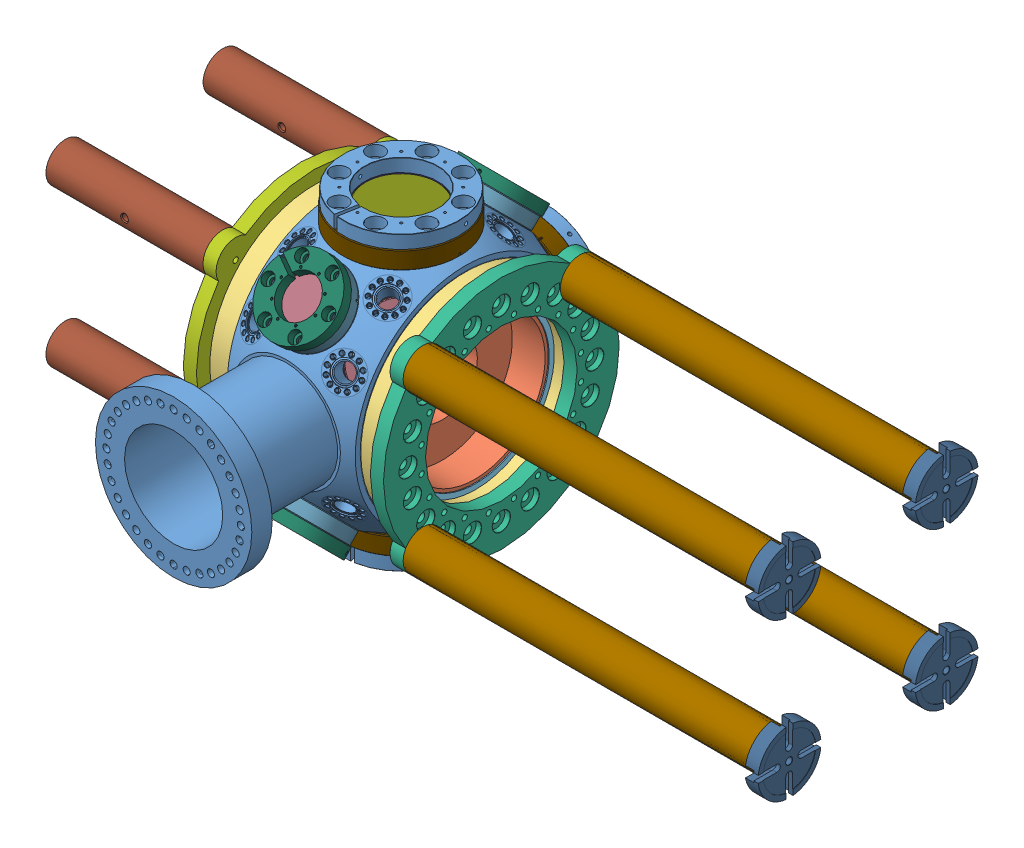
SolidWorks assembly Main Chamber Setup, configuration Default. Lengths in mm.
Overall size (770.13 358.68 400.02).
86 component instances, 19 part files, 50 mates.
Components (placement in the parent):
- Modified Kimball Chamber-1: Modified Kimball Chamber [Default] at (129.9941 206.5446 194.5806) size (246.45 225.02 343.9)
- Bucket Window-1: Bucket Window [Default] at (172.4884 96.353 297.4132) x (0 0.983185 -0.182612) z (0 0.182612 0.983185) size (236 64.03 236)
  - ISAdaptor-1: ISAdaptor [Default] at (127.1172 -28.8884 -80.9812) x (0.091876 0 -0.99577) z (-0.99577 0 -0.091876) size (142.24 51.09 142.24)
  - ISFlange-1: ISFlange [Default] at (127.1172 -30.6577 -80.9812) x (-0.182612 0 0.983185) z (-0.983185 0 -0.182612) size (202.44 22.35 202.44)
  - ISWindow-1: ISWindow [Default] at (127.1172 22.1997 -80.9812) size (68.33 6.35 68.33)
  - RecessedRing-1: RecessedRing [Default] at (127.1172 -52.3227 -80.9812) size (152.4 1 152.4)
- Bucket Window-2: Bucket Window [Default] at (87.4998 279.566 326.4313) x (0 -0.878634 -0.477495) z (0 -0.477495 0.878634) size (236 64.03 236)
  - ISAdaptor-1: ISAdaptor [Default] at (127.1172 -28.8884 -80.9812) x (0.091876 0 -0.99577) z (-0.99577 0 -0.091876) size (142.24 51.09 142.24)
  - ISFlange-1: ISFlange [Default] at (127.1172 -30.6577 -80.9812) x (-0.182612 0 0.983185) z (-0.983185 0 -0.182612) size (202.44 22.35 202.44)
  - ISWindow-1: ISWindow [Default] at (127.1172 22.1997 -80.9812) size (68.33 6.35 68.33)
  - RecessedRing-1: RecessedRing [Default] at (127.1172 -52.3227 -80.9812) size (152.4 1 152.4)
- Washer Chamber Base-1: Washer Chamber Base [Default] at (214.3221 206.5446 194.5806) x (0 -0.707107 0.707107) z (0 0.707107 0.707107) size (253.63 12.7 253.63)
- Washer Chamber Top-1: Washer Chamber Top [Default] at (45.6661 206.5446 194.5806) x (0 0.707107 0.707107) z (0 -0.707107 0.707107) size (253.63 12.7 253.63)
- Damped Post for Main Chamber Bottom-1: Damped Post for Main Chamber Bottom [Default] at (287.9394 108.1989 277.2908) x (0 0 1) z (-1 0 0) size (60.59 60.59 356.82)
  - Damped Post for Main Chamber P2_90322A235-1: Damped Post for Main Chamber P2_90322A235 [90322A235] at (-6.5102 22.1457 41.8672) size (32.66 32.53 40.54)
  - Damped Post for Main Chamber P2_90322A235-2: Damped Post for Main Chamber P2_90322A235 [90322A235] at (-6.5102 22.1457 -262.9328) x (-0.923728 -0.383049 0) z (0 0 -1) size (32.66 32.53 40.54)
  - Damped Post for Main Chamber Bottom P1-1: Damped Post for Main Chamber Bottom P1 [Default] at (-6.5102 22.1457 -281.9828) x (1 0 0) z (0 -1 0) size (38.1 342.9 38.1)
  - Damped Post for Main Chamber P3_PB2-1: Damped Post for Main Chamber P3_PB2 [Default] at (-6.5102 22.1457 -288.3328) x (1 0 0) z (0 -1 0) size (60.59 12.7 60.59)
- Damped Post for Main Chamber Bottom-2: Damped Post for Main Chamber Bottom [Default] at (287.9394 260.5989 277.2908) x (0 0 1) z (-1 0 0) size (60.59 60.59 356.82)
  - Damped Post for Main Chamber P2_90322A235-1: Damped Post for Main Chamber P2_90322A235 [90322A235] at (-6.5102 22.1457 41.8672) size (32.66 32.53 40.54)
  - Damped Post for Main Chamber P2_90322A235-2: Damped Post for Main Chamber P2_90322A235 [90322A235] at (-6.5102 22.1457 -262.9328) x (-0.923728 -0.383049 0) z (0 0 -1) size (32.66 32.53 40.54)
  - Damped Post for Main Chamber Bottom P1-1: Damped Post for Main Chamber Bottom P1 [Default] at (-6.5102 22.1457 -281.9828) x (1 0 0) z (0 -1 0) size (38.1 342.9 38.1)
  - Damped Post for Main Chamber P3_PB2-1: Damped Post for Main Chamber P3_PB2 [Default] at (-6.5102 22.1457 -288.3328) x (1 0 0) z (0 -1 0) size (60.59 12.7 60.59)
- Damped Post for Main Chamber Bottom-3: Damped Post for Main Chamber Bottom [Default] at (287.9394 108.1989 124.8908) x (0 0 1) z (-1 0 0) size (60.59 60.59 356.82)
  - Damped Post for Main Chamber P2_90322A235-1: Damped Post for Main Chamber P2_90322A235 [90322A235] at (-6.5102 22.1457 41.8672) size (32.66 32.53 40.54)
  - Damped Post for Main Chamber P2_90322A235-2: Damped Post for Main Chamber P2_90322A235 [90322A235] at (-6.5102 22.1457 -262.9328) x (-0.923728 -0.383049 0) z (0 0 -1) size (32.66 32.53 40.54)
  - Damped Post for Main Chamber Bottom P1-1: Damped Post for Main Chamber Bottom P1 [Default] at (-6.5102 22.1457 -281.9828) x (1 0 0) z (0 -1 0) size (38.1 342.9 38.1)
  - Damped Post for Main Chamber P3_PB2-1: Damped Post for Main Chamber P3_PB2 [Default] at (-6.5102 22.1457 -288.3328) x (1 0 0) z (0 -1 0) size (60.59 12.7 60.59)
- Damped Post for Main Chamber Bottom-4: Damped Post for Main Chamber Bottom [Default] at (287.9394 260.5989 124.8908) x (0 0 1) z (-1 0 0) size (60.59 60.59 356.82)
  - Damped Post for Main Chamber P2_90322A235-1: Damped Post for Main Chamber P2_90322A235 [90322A235] at (-6.5102 22.1457 41.8672) size (32.66 32.53 40.54)
  - Damped Post for Main Chamber P2_90322A235-2: Damped Post for Main Chamber P2_90322A235 [90322A235] at (-6.5102 22.1457 -262.9328) x (-0.923728 -0.383049 0) z (0 0 -1) size (32.66 32.53 40.54)
  - Damped Post for Main Chamber Bottom P1-1: Damped Post for Main Chamber Bottom P1 [Default] at (-6.5102 22.1457 -281.9828) x (1 0 0) z (0 -1 0) size (38.1 342.9 38.1)
  - Damped Post for Main Chamber P3_PB2-1: Damped Post for Main Chamber P3_PB2 [Default] at (-6.5102 22.1457 -288.3328) x (1 0 0) z (0 -1 0) size (60.59 12.7 60.59)
- Chamber Top Post_P6-5: Chamber Top Post_P6 [Default] at (-42.0322 295.4786 112.4775) x (0 1 0) z (0 0 1) size (37.74 220.47 37.75)
- Chamber Top Post_P6-6: Chamber Top Post_P6 [Default] at (-42.0322 143.0786 112.4775) x (0 1 0) z (0 0 1) size (37.74 220.47 37.75)
- Chamber Top Post_P6-7: Chamber Top Post_P6 [Default] at (-42.0322 295.4786 264.8775) x (0 1 0) z (0 0 1) size (37.74 220.47 37.75)
- Chamber Top Post_P6-8: Chamber Top Post_P6 [Default] at (-42.0322 143.0786 264.8775) x (0 1 0) z (0 0 1) size (37.74 220.47 37.75)
- 2.75 VP Assembly-1: 2.75 VP Assembly [Default] at (180.0634 70.3465 285.9142) x (0 0.707107 0.707107) z (-1 0 0) size (98.89 22.87 98.89)
  - 2.75 Window-1: 2.75 Window [Default] at (8.7044 2.1311 10.9274) size (69.34 12.71 69.34)
    - 2.75 Window P1-1: 2.75 Window P1 [Default] at (7.3044 10.0797 3.9869) size (56.02 10.92 56.02)
      - 2.75 Window P1-1-1: 2.75 Window P1-1 [Default] at (15.7152 13.9203 35.1549) size (44.88 10.92 44.88)
      - 2.75 Window P1-2-1: 2.75 Window P1-2 [Default] at (15.7152 20.9053 35.1549) x (0.940252 0 0.340481) z (0 -1 0) size (43.74 43.74 3.17)
    - 2.75 Window P2-1: 2.75 Window P2 [Default] at (23.0196 40.5099 39.1419) x (0 -1 0) z (0 0 1) size (12.71 69.34 69.34)
  - Viewport Washer 2.75-1: Viewport Washer 2.75 [Default] at (31.724 29.9411 50.0692) x (0.5 0 0.866025) z (0 -1 0) size (72.39 72.39 10.16)
- 2.75 VP Assembly-2: 2.75 VP Assembly [Default] at (127.5549 278.4333 350.2236) x (0.866025 0.353553 -0.353553) z (-0.5 0.612372 -0.612372) size (98.89 22.87 98.89)
  - 2.75 Window-1: 2.75 Window [Default] at (8.7044 2.1311 10.9274) size (69.34 12.71 69.34)
    - 2.75 Window P1-1: 2.75 Window P1 [Default] at (7.3044 10.0797 3.9869) size (56.02 10.92 56.02)
      - 2.75 Window P1-1-1: 2.75 Window P1-1 [Default] at (15.7152 13.9203 35.1549) size (44.88 10.92 44.88)
      - 2.75 Window P1-2-1: 2.75 Window P1-2 [Default] at (15.7152 20.9053 35.1549) x (0.940252 0 0.340481) z (0 -1 0) size (43.74 43.74 3.17)
    - 2.75 Window P2-1: 2.75 Window P2 [Default] at (23.0196 40.5099 39.1419) x (0 -1 0) z (0 0 1) size (12.71 69.34 69.34)
  - Viewport Washer 2.75-1: Viewport Washer 2.75 [Default] at (31.724 29.9411 50.0692) x (0.5 0 0.866025) z (0 -1 0) size (72.39 72.39 10.16)
- 2.75 VP Assembly-3: 2.75 VP Assembly [Default] at (127.5549 362.1876 122.6919) x (0.866025 -0.353553 -0.353553) z (-0.5 -0.612372 -0.612372) size (98.89 22.87 98.89)
  - 2.75 Window-1: 2.75 Window [Default] at (8.7044 2.1311 10.9274) size (69.34 12.71 69.34)
    - 2.75 Window P1-1: 2.75 Window P1 [Default] at (7.3044 10.0797 3.9869) size (56.02 10.92 56.02)
      - 2.75 Window P1-1-1: 2.75 Window P1-1 [Default] at (15.7152 13.9203 35.1549) size (44.88 10.92 44.88)
      - 2.75 Window P1-2-1: 2.75 Window P1-2 [Default] at (15.7152 20.9053 35.1549) x (0.940252 0 0.340481) z (0 -1 0) size (43.74 43.74 3.17)
    - 2.75 Window P2-1: 2.75 Window P2 [Default] at (23.0196 40.5099 39.1419) x (0 -1 0) z (0 0 1) size (12.71 69.34 69.34)
  - Viewport Washer 2.75-1: Viewport Washer 2.75 [Default] at (31.724 29.9411 50.0692) x (0.5 0 0.866025) z (0 -1 0) size (72.39 72.39 10.16)
- 2.75 VP Assembly-4: 2.75 VP Assembly [Default] at (127.5549 134.656 38.9376) x (0.866025 -0.353553 0.353553) z (-0.5 -0.612372 0.612372) size (98.89 22.87 98.89)
  - 2.75 Window-1: 2.75 Window [Default] at (8.7044 2.1311 10.9274) size (69.34 12.71 69.34)
    - 2.75 Window P1-1: 2.75 Window P1 [Default] at (7.3044 10.0797 3.9869) size (56.02 10.92 56.02)
      - 2.75 Window P1-1-1: 2.75 Window P1-1 [Default] at (15.7152 13.9203 35.1549) size (44.88 10.92 44.88)
      - 2.75 Window P1-2-1: 2.75 Window P1-2 [Default] at (15.7152 20.9053 35.1549) x (0.940252 0 0.340481) z (0 -1 0) size (43.74 43.74 3.17)
    - 2.75 Window P2-1: 2.75 Window P2 [Default] at (23.0196 40.5099 39.1419) x (0 -1 0) z (0 0 1) size (12.71 69.34 69.34)
  - Viewport Washer 2.75-1: Viewport Washer 2.75 [Default] at (31.724 29.9411 50.0692) x (0.5 0 0.866025) z (0 -1 0) size (72.39 72.39 10.16)
- 4.5 VP Assembly-1: 4.5 VP Assembly [Default] at (63.6272 104.8035 99.6116) x (0 -1 0) z (0 0 1) size (29.97 146.69 146.69)
  - Viewport 4.5_9722007-1: Viewport 4.5_9722007 [Default] at (9.7649 66.3669 94.969) size (17.27 113.54 113.54)
    - 1004602A-1: 1004602A [Default] at (1.2954 0 0) x (0 1 0) z (-1 0 0) size (73.79 73.79 15.62)
      - 1002203A-1: 1002203A [Default] at (0 0 -9.271) x (-1 0 0) z (0 0 -1) size (72.01 72.01 6.35)
      - Viewport 4.5 P1_0194302B-1: Viewport 4.5 P1_0194302B [Default] at origin size (73.79 73.79 15.49)
    - Viewport 4.5 P2_0194603B-1: Viewport 4.5 P2_0194603B [Default] at origin size (17.27 113.54 113.54)
  - Viewport Washer 4.5-1: Viewport Washer 4.5 [Default] at (27.0369 66.3669 94.969) x (0 0.382683 -0.92388) z (1 0 0) size (112.27 112.27 12.7)
- 4.5 VP Assembly-2: 4.5 VP Assembly [Default] at (16.8567 181.5727 92.8395) x (0 0 -1) z (0.92388 -0.382683 0) size (29.97 146.69 146.69)
  - Viewport 4.5_9722007-1: Viewport 4.5_9722007 [Default] at (9.7649 66.3669 94.969) size (17.27 113.54 113.54)
    - 1004602A-1: 1004602A [Default] at (1.2954 0 0) x (0 1 0) z (-1 0 0) size (73.79 73.79 15.62)
      - 1002203A-1: 1002203A [Default] at (0 0 -9.271) x (-1 0 0) z (0 0 -1) size (72.01 72.01 6.35)
      - Viewport 4.5 P1_0194302B-1: Viewport 4.5 P1_0194302B [Default] at origin size (73.79 73.79 15.49)
    - Viewport 4.5 P2_0194603B-1: Viewport 4.5 P2_0194603B [Default] at origin size (17.27 113.54 113.54)
  - Viewport Washer 4.5-1: Viewport Washer 4.5 [Default] at (27.0369 66.3669 94.969) x (0 0.382683 -0.92388) z (1 0 0) size (112.27 112.27 12.7)
- 4.5 VP Assembly-3: 4.5 VP Assembly [Default] at (196.361 308.2857 99.6116) x (0 1 0) z (0 0 1) size (29.97 146.69 146.69)
  - Viewport 4.5_9722007-1: Viewport 4.5_9722007 [Default] at (9.7649 66.3669 94.969) size (17.27 113.54 113.54)
    - 1004602A-1: 1004602A [Default] at (1.2954 0 0) x (0 1 0) z (-1 0 0) size (73.79 73.79 15.62)
      - 1002203A-1: 1002203A [Default] at (0 0 -9.271) x (-1 0 0) z (0 0 -1) size (72.01 72.01 6.35)
      - Viewport 4.5 P1_0194302B-1: Viewport 4.5 P1_0194302B [Default] at origin size (73.79 73.79 15.49)
    - Viewport 4.5 P2_0194603B-1: Viewport 4.5 P2_0194603B [Default] at origin size (17.27 113.54 113.54)
  - Viewport Washer 4.5-1: Viewport Washer 4.5 [Default] at (27.0369 66.3669 94.969) x (0 0.382683 -0.92388) z (1 0 0) size (112.27 112.27 12.7)
Mates (geometry in assembly coordinates):
- Coincident1: coincident anti-aligned: plane of Modified Kimball Chamber-1 through (191.9701 120.8196 194.5806) normal (1 0 0); plane of Bucket Window-1/ISFlange-1 through (191.9701 206.5446 295.7996) normal (-1 0 0)
- Concentric1: concentric anti-aligned: circle of Modified Kimball Chamber-1; circle of Bucket Window-1/ISFlange-1
- Concentric2: concentric anti-aligned: circle of Modified Kimball Chamber-1; circle of Bucket Window-1/ISFlange-1
- Coincident12: coincident anti-aligned: plane of Modified Kimball Chamber-1 through (68.0181 120.8196 194.5806) normal (-1 0 0); plane of Bucket Window-2/ISFlange-1 through (68.0181 175.2662 290.8456) normal (1 0 0)
- Concentric9: concentric aligned: circle of Bucket Window-2/ISFlange-1; circle of Modified Kimball Chamber-1
- Concentric10: concentric anti-aligned: circle of Modified Kimball Chamber-1; circle of Bucket Window-2/ISFlange-1
- Coincident13: coincident anti-aligned: plane of Bucket Window-1/ISFlange-1 through (214.3221 206.5446 270.6536) normal (1 0 0); plane of Washer Chamber Base-1 through (214.3221 206.5446 194.5806) normal (-1 0 0)
- Concentric12: concentric anti-aligned: circle of Bucket Window-1/ISFlange-1; circle of Washer Chamber Base-1
- Concentric13: concentric aligned: circle of Modified Kimball Chamber-1; circle of Washer Chamber Base-1
- Coincident23: coincident anti-aligned: plane of Bucket Window-2/ISFlange-1 through (45.6661 183.0368 266.9303) normal (-1 0 0); plane of Washer Chamber Top-1 through (45.6661 206.5446 194.5806) normal (1 0 0)
- Parallel1: parallel anti-aligned: line of Washer Chamber Base-1 through (227.0221 130.3446 270.7806) axis (0 1 0); line of Washer Chamber Top-1 through (32.9661 282.7446 270.7806) axis (0 -1 0)
- Concentric26: concentric anti-aligned: circle of Bucket Window-2/ISFlange-1; circle of Washer Chamber Top-1
- Concentric27: concentric anti-aligned: circle of Bucket Window-2/ISAdaptor-1; circle of Washer Chamber Base-1
- Coincident38: coincident anti-aligned: plane of Washer Chamber Base-1 through (227.0221 206.5446 194.5806) normal (1 0 0); plane of Damped Post for Main Chamber Bottom-4/Damped Post for Main Chamber Bottom P1-1 through (227.0221 282.7446 118.3806) normal (-1 0 0)
- Concentric41: concentric aligned: circle of Washer Chamber Base-1; circle of Damped Post for Main Chamber Bottom-4/Damped Post for Main Chamber P2_90322A235-1
- Coincident39: coincident anti-aligned: plane of Washer Chamber Base-1 through (227.0221 206.5446 194.5806) normal (1 0 0); plane of Damped Post for Main Chamber Bottom-3/Damped Post for Main Chamber Bottom P1-1 through (227.0221 130.3446 118.3806) normal (-1 0 0)
- Concentric42: concentric aligned: circle of Washer Chamber Base-1; circle of Damped Post for Main Chamber Bottom-3/Damped Post for Main Chamber P2_90322A235-1
- Coincident40: coincident anti-aligned: plane of Washer Chamber Base-1 through (227.0221 206.5446 194.5806) normal (1 0 0); plane of Damped Post for Main Chamber Bottom-1/Damped Post for Main Chamber Bottom P1-1 through (227.0221 130.3446 270.7806) normal (-1 0 0)
- Concentric43: concentric aligned: circle of Washer Chamber Base-1; circle of Damped Post for Main Chamber Bottom-1/Damped Post for Main Chamber P2_90322A235-1
- Coincident41: coincident anti-aligned: plane of Washer Chamber Base-1 through (227.0221 206.5446 194.5806) normal (1 0 0); plane of Damped Post for Main Chamber Bottom-2/Damped Post for Main Chamber Bottom P1-1 through (227.0221 282.7446 270.7806) normal (-1 0 0)
- Concentric44: concentric aligned: circle of Washer Chamber Base-1; circle of Damped Post for Main Chamber Bottom-2/Damped Post for Main Chamber P2_90322A235-1
- Coincident42: coincident anti-aligned: plane of Washer Chamber Top-1 through (32.9661 206.5446 194.5806) normal (-1 0 0); plane of Chamber Top Post_P6-5 through (32.9661 285.9196 118.3806) normal (1 0 0)
- Concentric45: concentric anti-aligned: circle of Washer Chamber Top-1; circle of Chamber Top Post_P6-5
- Coincident43: coincident anti-aligned: plane of Washer Chamber Top-1 through (32.9661 206.5446 194.5806) normal (-1 0 0); plane of Chamber Top Post_P6-6 through (32.9661 133.5196 118.3806) normal (1 0 0)
- Concentric46: concentric anti-aligned: circle of Washer Chamber Top-1; circle of Chamber Top Post_P6-6
- Coincident44: coincident anti-aligned: plane of Washer Chamber Top-1 through (32.9661 206.5446 194.5806) normal (-1 0 0); plane of Chamber Top Post_P6-7 through (32.9661 285.9196 270.7806) normal (1 0 0)
- Concentric47: concentric anti-aligned: circle of Washer Chamber Top-1; circle of Chamber Top Post_P6-7
- Coincident45: coincident anti-aligned: plane of Washer Chamber Top-1 through (32.9661 206.5446 194.5806) normal (-1 0 0); plane of Chamber Top Post_P6-8 through (32.9661 133.5196 270.7806) normal (1 0 0)
- Concentric48: concentric anti-aligned: circle of Washer Chamber Top-1; circle of Chamber Top Post_P6-8
- Coincident54: coincident anti-aligned: plane of Modified Kimball Chamber-1 through (191.9701 265.6426 86.4505) normal (0 0.707107 -0.707107); plane of 2.75 VP Assembly-3/2.75 Window-1/2.75 Window P2-1 through (129.9941 290.1587 110.9666) normal (0 -0.707107 0.707107)
- Concentric62: concentric aligned: circle of Modified Kimball Chamber-1; circle of 2.75 VP Assembly-3/2.75 Window-1/2.75 Window P2-1
- Concentric63: concentric anti-aligned: circle of Modified Kimball Chamber-1; circle of 2.75 VP Assembly-3/2.75 Window-1/2.75 Window P1-1/2.75 Window P1-1-1
- Coincident55: coincident anti-aligned: plane of Modified Kimball Chamber-1 through (191.9701 314.6748 253.6785) normal (0 0.707107 0.707107); plane of 2.75 VP Assembly-2/2.75 Window-1/2.75 Window P2-1 through (129.9941 290.1587 278.1946) normal (0 -0.707107 -0.707107)
- Concentric64: concentric anti-aligned: circle of Modified Kimball Chamber-1; circle of 2.75 VP Assembly-2/2.75 Window-1/2.75 Window P2-1
- Concentric65: concentric anti-aligned: circle of Modified Kimball Chamber-1; circle of 2.75 VP Assembly-2/2.75 Window-1/2.75 Window P2-1
- Coincident56: coincident anti-aligned: plane of Modified Kimball Chamber-1 through (191.9701 147.4467 302.7107) normal (0 -0.707107 0.707107); plane of 2.75 VP Assembly-1/2.75 Window-1/2.75 Window P2-1 through (129.9941 122.9306 278.1946) normal (0 0.707107 -0.707107)
- Concentric66: concentric anti-aligned: circle of Modified Kimball Chamber-1; circle of 2.75 VP Assembly-1/2.75 Window-1/2.75 Window P2-1
- Concentric67: concentric anti-aligned: circle of Modified Kimball Chamber-1; circle of 2.75 VP Assembly-1/2.75 Window-1/2.75 Window P2-1
- Coincident57: coincident anti-aligned: plane of Modified Kimball Chamber-1 through (191.9701 98.4145 135.4827) normal (0 -0.707107 -0.707107); plane of 2.75 VP Assembly-4/2.75 Window-1/2.75 Window P2-1 through (129.9941 122.9306 110.9666) normal (0 0.707107 0.707107)
- Concentric68: concentric anti-aligned: circle of Modified Kimball Chamber-1; circle of 2.75 VP Assembly-4/2.75 Window-1/2.75 Window P2-1
- Concentric69: concentric anti-aligned: circle of Modified Kimball Chamber-1; circle of 2.75 VP Assembly-4/2.75 Window-1/2.75 Window P2-1
- Coincident59: coincident anti-aligned: plane of Modified Kimball Chamber-1 through (191.9701 95.0386 247.0316) normal (0 -1 0); plane of 4.5 VP Assembly-1/Viewport 4.5_9722007-1/Viewport 4.5 P2_0194603B-1 through (129.9941 95.0386 194.5806) normal (0 1 0)
- Concentric70: concentric aligned: circle of Modified Kimball Chamber-1; circle of 4.5 VP Assembly-1/Viewport Washer 4.5-1
- Concentric71: concentric aligned: circle of Modified Kimball Chamber-1; circle of 4.5 VP Assembly-1/Viewport Washer 4.5-1
- Coincident61: coincident anti-aligned: plane of Modified Kimball Chamber-1 through (191.9701 154.0936 83.0746) normal (0 0 -1); plane of 4.5 VP Assembly-2/Viewport 4.5_9722007-1/Viewport 4.5 P2_0194603B-1 through (129.9941 206.5446 83.0746) normal (0 0 1)
- Concentric72: concentric aligned: circle of Modified Kimball Chamber-1; circle of 4.5 VP Assembly-2/Viewport Washer 4.5-1
- Concentric73: concentric aligned: circle of Modified Kimball Chamber-1; circle of 4.5 VP Assembly-2/Viewport 4.5_9722007-1/Viewport 4.5 P2_0194603B-1
- Coincident62: coincident anti-aligned: plane of Modified Kimball Chamber-1 through (191.9701 318.0506 142.1296) normal (0 1 0); plane of 4.5 VP Assembly-3/Viewport 4.5_9722007-1/Viewport 4.5 P2_0194603B-1 through (129.9941 318.0506 194.5806) normal (0 -1 0)
- Concentric74: concentric aligned: circle of Modified Kimball Chamber-1; circle of 4.5 VP Assembly-3/Viewport Washer 4.5-1
- Concentric75: concentric anti-aligned: circle of Modified Kimball Chamber-1; circle of 4.5 VP Assembly-3/Viewport Washer 4.5-1
